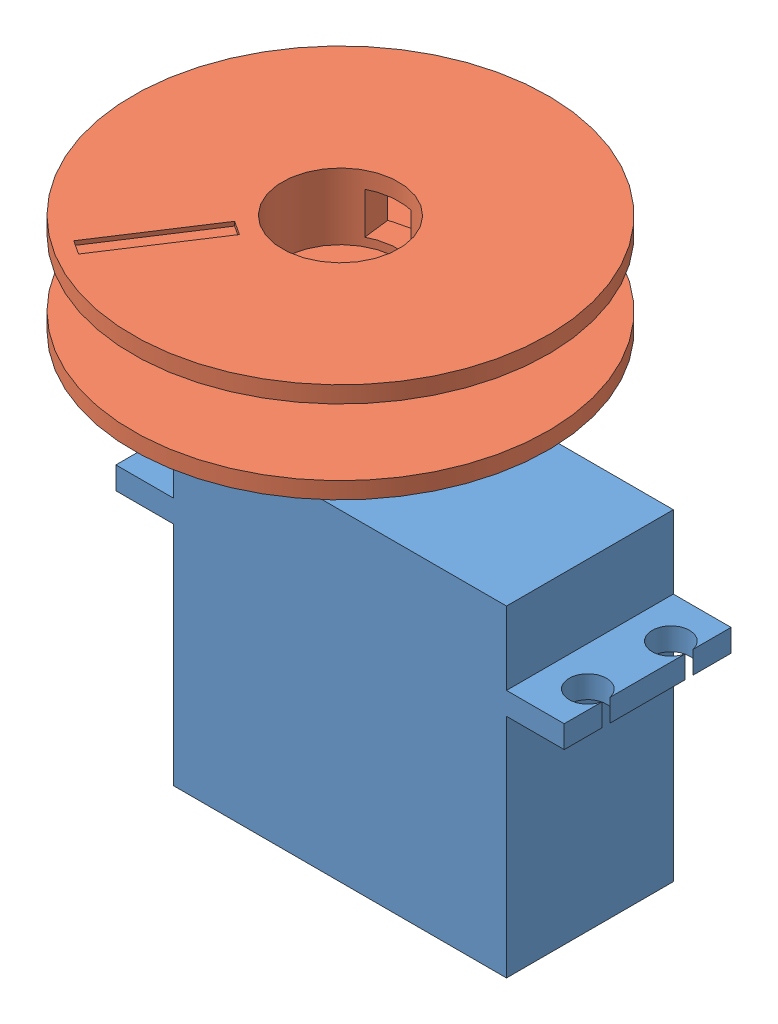
SolidWorks assembly motor, configuration ﾃﾞﾌｫﾙﾄ. Lengths in mm.
Overall size (73.36 59.5 70.97).
2 component instances, 2 part files, 6 mates.
Components (placement in the parent):
- FB5311M-1: FB5311M [ﾃﾞﾌｫﾙﾄ] at origin size (54 44.25 20.1)
- servo_horn_short-1: servo_horn_short [ﾃﾞﾌｫﾙﾄ] at (-10 42.5 0) x (-0.837169 0 -0.546944) z (0 1 0) size (50 57.04 17)
Mates (geometry in assembly coordinates):
- 同心円1: concentric aligned: cylinder of FB5311M-1 through (-10 52.7353 0) axis (0 -1 0) radius 3; cylinder of pulley-1 through (-10 44.25 0) axis (0 -1 0) radius 25
- 一致1: coincident anti-aligned: plane of FB5311M-1 through (0 44.25 0) normal (0 1 0); plane of pulley-1 through (-10 44.25 0) normal (0 -1 0)
- 同心円2: concentric aligned: cylinder of FB5311M-1 through (-10 52.7353 0) axis (0 -1 0) radius 3; cylinder of servo_horn-1 through (-10 47.5 0) axis (0 -1 0) radius 13
- 距離1: distance = 6.2 mm anti-aligned: plane of FB5311M-1 through (0 38.8 0) normal (0 1 0); plane of servo_horn-1 through (-23.4795 45 -0.7436) normal (0 -1 0)
- 同心円3: concentric aligned: cylinder of FB5311M-1 through (-10 52.7353 0) axis (0 -1 0) radius 3; cylinder of servo_horn_short-1 through (-10 47.5 0) axis (0 -1 0) radius 13
- 距離2: distance = 6.2 mm anti-aligned: plane of FB5311M-1 through (0 38.8 0) normal (0 1 0); plane of servo_horn_short-1 through (-23.18 45 -0.7271) normal (0 -1 0)
